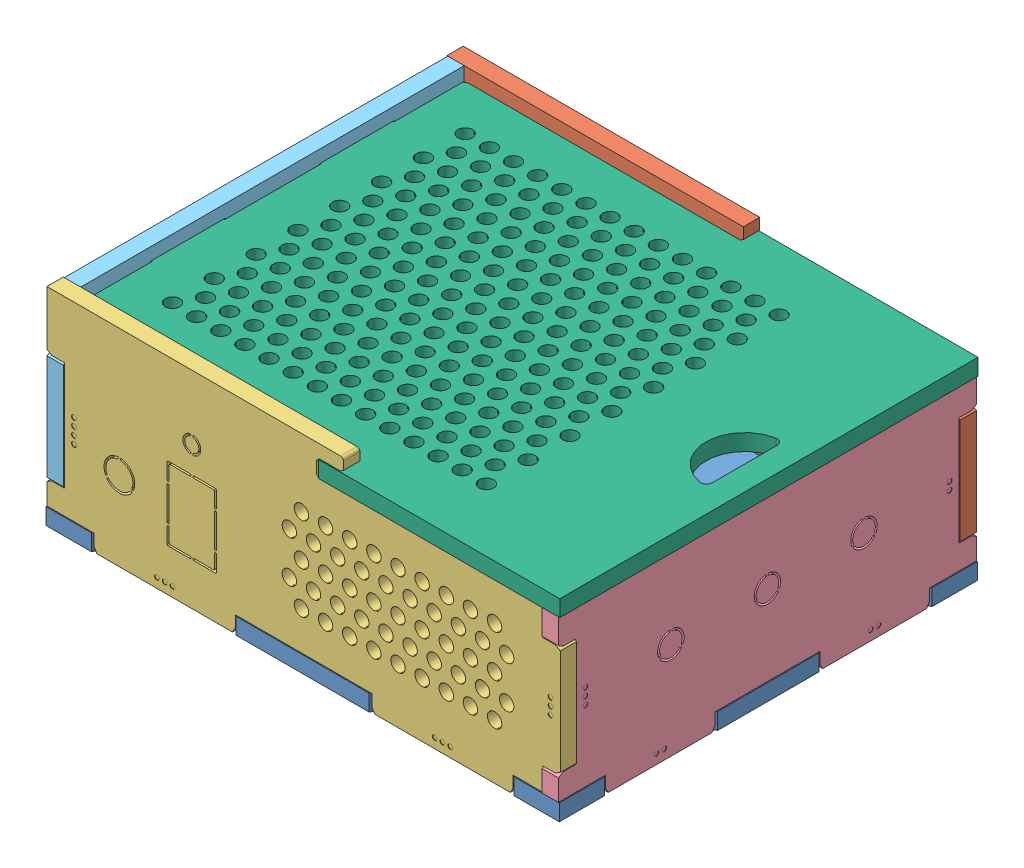
SolidWorks assembly Laser Cut Box, Masonite (0.17in), Type 1, configuration Default. Lengths in mm.
Overall size (135.13 54.32 110).
6 component instances, 6 part files, 18 mates.
Components (placement in the parent):
- Floor,  Laser Cut Box, Masonite (0.17in), Type 1-1: Floor,  Laser Cut Box, Masonite (0.17in), Type 1 [Default] at (72.396 52.9582 103.8967) size (135 4.32 110)
- Right Wall, Laser Cut Box, Masonite (0.17in), Type 1-1: Right Wall, Laser Cut Box, Masonite (0.17in), Type 1 [Default] at (72.396 82.2762 49.1507) x (1 0 0) z (0 -1 0) size (135 4.32 54.32)
- Left Wall, Laser Cut Box, Masonite (0.17in), Type 1-3: Left Wall, Laser Cut Box, Masonite (0.17in), Type 1 [Default] at (72.396 82.2762 154.3247) x (1 0 0) z (0 -1 0) size (135 4.32 54.32)
- Front Wall, Laser Cut Box, Masonite (0.17in), Type 1-1: Front Wall, Laser Cut Box, Masonite (0.17in), Type 1 [Default] at (139.642 82.2762 103.8967) x (0 0 1) z (0 -1 0) size (110 4.32 46.57)
- Back Wall, Laser Cut Box, Masonite (0.17in), Type 1-1: Back Wall, Laser Cut Box, Masonite (0.17in), Type 1 [Default] at (5.15 82.2762 103.8967) x (0 0 -1) z (0 -1 0) size (110 4.32 54.32)
- Lid_v2, Laser Cut Box, Masonite (0.17in), Type 1-1: Lid_v2, Laser Cut Box, Masonite (0.17in), Type 1 [Default] at (72.523 99.5292 103.8967) x (-1 0 0) z (0 0 -1) size (135 4.32 110)
Mates (geometry in assembly coordinates):
- Coincident1: coincident anti-aligned: plane of Floor,  Laser Cut Box, Masonite (0.17in), Type 1-1 through (72.396 57.2762 103.8967) normal (0 1 0); plane of Wood Box, Type 1, Right Wall-1 through (4.896 57.2762 53.4687) normal (0 -1 0)
- Coincident2: coincident anti-aligned: plane of Floor,  Laser Cut Box, Masonite (0.17in), Type 1-1 through (90.6627 52.9572 53.4687) normal (0 0 -1); plane of Wood Box, Type 1, Right Wall-1 through (72.396 82.2762 53.4687) normal (0 0 1)
- Width1: width anti-aligned: plane of Floor,  Laser Cut Box, Masonite (0.17in), Type 1-1 through (54.1294 52.9572 48.8967) normal (-1 0 0); plane of Floor,  Laser Cut Box, Masonite (0.17in), Type 1-1 through (90.6627 52.9572 48.8967) normal (1 0 0); plane of Right Wall, Laser Cut Box, Masonite (0.17in), Type 1-1 through (54.4469 52.9582 90.887) normal (1 0 0); plane of Right Wall, Laser Cut Box, Masonite (0.17in), Type 1-1 through (90.3452 57.2762 90.887) normal (-1 0 0)
- Width2: width aligned: plane of Floor,  Laser Cut Box, Masonite (0.17in), Type 1-1 through (90.6627 52.9572 158.8967) normal (1 0 0); plane of Floor,  Laser Cut Box, Masonite (0.17in), Type 1-1 through (54.1294 52.9572 158.8967) normal (-1 0 0); plane of Left Wall, Laser Cut Box, Masonite (0.17in), Type 1-3 through (54.4469 52.9582 196.061) normal (1 0 0); plane of Left Wall, Laser Cut Box, Masonite (0.17in), Type 1-3 through (90.3452 57.2762 196.061) normal (-1 0 0)
- Coincident4: coincident anti-aligned: plane of Floor,  Laser Cut Box, Masonite (0.17in), Type 1-1 through (72.396 57.2762 103.8967) normal (0 1 0); plane of Wood Box, Type 1, Left Wall-3 through (4.896 57.2762 158.6427) normal (0 -1 0)
- Coincident5: coincident anti-aligned: plane of Floor,  Laser Cut Box, Masonite (0.17in), Type 1-1 through (17.596 52.9572 154.3247) normal (0 0 1); plane of Wood Box, Type 1, Left Wall-3 through (72.396 82.2762 154.3247) normal (0 0 -1)
- Width3: width anti-aligned: plane of Floor,  Laser Cut Box, Masonite (0.17in), Type 1-1 through (139.896 52.9572 89.7967) normal (0 0 -1); plane of Floor,  Laser Cut Box, Masonite (0.17in), Type 1-1 through (139.896 52.9572 117.9967) normal (0 0 1); plane of Front Wall, Laser Cut Box, Masonite (0.17in), Type 1-1 through (106.1675 52.9582 90.1142) normal (0 0 1); plane of Front Wall, Laser Cut Box, Masonite (0.17in), Type 1-1 through (106.1675 57.2762 117.6792) normal (0 0 -1)
- Width4: width anti-aligned: plane of Floor,  Laser Cut Box, Masonite (0.17in), Type 1-1 through (4.896 52.9572 89.7967) normal (0 0 -1); plane of Floor,  Laser Cut Box, Masonite (0.17in), Type 1-1 through (4.896 52.9572 117.9967) normal (0 0 1); plane of Back Wall, Laser Cut Box, Masonite (0.17in), Type 1-1 through (38.6246 57.2762 90.1142) normal (0 0 1); plane of Back Wall, Laser Cut Box, Masonite (0.17in), Type 1-1 through (38.6246 52.9582 117.6792) normal (0 0 -1)
- Coincident6: coincident anti-aligned: plane of Floor,  Laser Cut Box, Masonite (0.17in), Type 1-1 through (72.396 57.2762 103.8967) normal (0 1 0); plane of Back Wall, Laser Cut Box, Masonite (0.17in), Type 1-1 through (9.468 57.2762 158.8967) normal (0 -1 0)
- Coincident7: coincident anti-aligned: plane of Floor,  Laser Cut Box, Masonite (0.17in), Type 1-1 through (9.468 52.9572 61.5967) normal (-1 0 0); plane of Back Wall, Laser Cut Box, Masonite (0.17in), Type 1-1 through (9.468 82.2762 103.8967) normal (1 0 0)
- Coincident8: coincident anti-aligned: plane of Floor,  Laser Cut Box, Masonite (0.17in), Type 1-1 through (72.396 57.2762 103.8967) normal (0 1 0); plane of Wood Box, Type 1, Front Wall-1 through (135.324 57.2762 48.8967) normal (0 -1 0)
- Coincident9: coincident anti-aligned: plane of Floor,  Laser Cut Box, Masonite (0.17in), Type 1-1 through (135.324 52.9572 61.5967) normal (1 0 0); plane of Wood Box, Type 1, Front Wall-1 through (135.324 82.2762 103.8967) normal (-1 0 0)
- Width5: width anti-aligned: plane of Wood Box, Type 1, Lid-1 through (4.134 99.5282 53.4687) normal (0 0 -1); plane of Wood Box, Type 1, Lid-1 through (4.134 99.5282 49.1507) normal (0 0 1); plane of Right Wall, Laser Cut Box, Masonite (0.17in), Type 1-1 through (72.396 82.2762 53.4687) normal (0 0 1); plane of Right Wall, Laser Cut Box, Masonite (0.17in), Type 1-1 through (72.396 82.2762 49.1507) normal (0 0 -1)
- Coincident10: coincident anti-aligned: plane of Right Wall, Laser Cut Box, Masonite (0.17in), Type 1-1 through (75.761 99.5292 49.1497) normal (0 1 0); plane of Wood Box, Type 1, Lid-1 through (71.634 99.5292 104.1507) normal (0 -1 0)
- Coincident11: coincident anti-aligned: plane of Wood Box, Type 1, Right Wall-1 through (75.634 104.1012 49.1497) normal (1 0 0); plane of Wood Box, Type 1, Lid-1 through (75.634 99.5282 53.4687) normal (-1 0 0)
- Width6: width anti-aligned: plane of Right Wall, Laser Cut Box, Masonite (0.17in), Type 1-1 through (72.396 82.2762 53.4687) normal (0 0 1); plane of Left Wall, Laser Cut Box, Masonite (0.17in), Type 1-3 through (72.396 82.2762 154.3247) normal (0 0 -1); plane of Lid_v2, Laser Cut Box, Masonite (0.17in), Type 1-1 through (5.023 99.5282 53.2237) normal (0 0 -1); plane of Lid_v2, Laser Cut Box, Masonite (0.17in), Type 1-1 through (5.023 99.5282 154.5697) normal (0 0 1)
- Coincident13: coincident anti-aligned: plane of Wood Box, Type 1, Left Wall-3 through (75.761 99.5292 154.3237) normal (0 1 0); plane of Wood Box, Type 1, Lid_v2-1 through (72.523 99.5292 103.8967) normal (0 -1 0)
- Coincident14: coincident: cylinder of Wood Box, Type 1, Left Wall-3 through (76.523 100.2912 154.3237) axis (0 0 -1) radius 0.762; line of Wood Box, Type 1, Lid_v2-1 through (76.523 99.5292 154.5697) axis (0 0 1)
